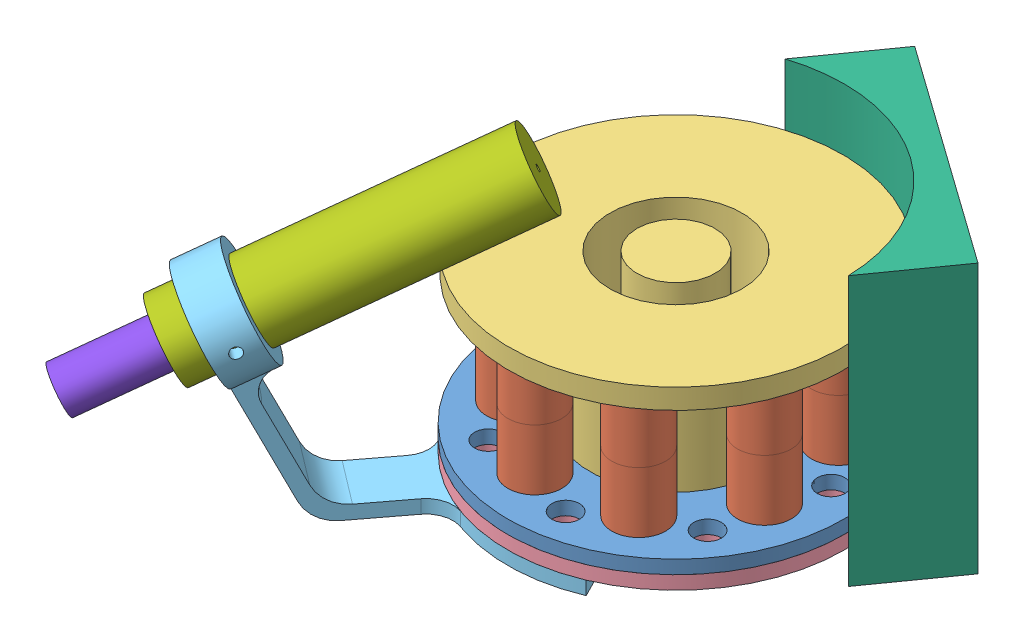
SolidWorks assembly Aseembly-FENG-BN7Q8T2, configuration Default. Lengths in mm.
Overall size (83.54 59.24 90.91).
26 component instances, 9 part files, 27 mates.
Components (placement in the parent):
- base_plate-3: base_plate [Default] at (-36.646 29.2594 17.7308) size (50 8 50)
- magnet_cyclo180-17: magnet_cyclo180 [Default] at (-36.646 30.2594 17.7308) x (-0.894675 0 0.446717) z (-0.446717 0 -0.894675) size (8 10 8)
- magnet_cyclo180-18: magnet_cyclo180 [Default] at (-27.3545 30.2594 32.5604) x (0.951763 0 -0.306835) z (0.306835 0 0.951763) size (8 10 8)
- magnet_cyclo180-19: magnet_cyclo180 [Default] at (-40.562 30.2594 34.787) x (0.889963 0 0.456033) z (-0.456033 0 0.889963) size (8 10 8)
- magnet_cyclo180-20: magnet_cyclo180 [Default] at (-51.4756 30.2594 27.0223) x (0.306835 0 0.951763) z (-0.951763 0 0.306835) size (8 10 8)
- magnet_cyclo180-21: magnet_cyclo180 [Default] at (-53.7022 30.2594 13.8147) x (-0.456033 0 0.889963) z (-0.889963 0 -0.456033) size (8 10 8)
- magnet_cyclo180-22: magnet_cyclo180 [Default] at (-45.9375 30.2594 2.9011) x (-0.951763 0 0.306835) z (-0.306835 0 -0.951763) size (8 10 8)
- magnet_cyclo180-23: magnet_cyclo180 [Default] at (-32.7299 30.2594 0.6746) x (-0.889963 0 -0.456033) z (0.456033 0 -0.889963) size (8 10 8)
- magnet_cyclo180-24: magnet_cyclo180 [Default] at (-21.8164 30.2594 8.4393) x (-0.306835 0 -0.951763) z (0.951763 0 -0.306835) size (8 10 8)
- magnet_cyclo180-25: magnet_cyclo180 [Default] at (-19.5898 30.2594 21.6468) x (0.456033 0 -0.889963) z (0.889963 0 0.456033) size (8 10 8)
- insulator-2: insulator [Default] at (-36.646 31.2594 17.7308) x (0.874558 0 0.48492) z (0 1 0) size (49.6 49.6 22)
- magnet_cyclo180-26: magnet_cyclo180 [Default] at (-51.4756 40.2594 27.0223) x (0.306835 0 0.951763) z (-0.951763 0 0.306835) size (8 10 8)
- magnet_cyclo180-27: magnet_cyclo180 [Default] at (-36.646 40.2594 17.7308) x (-0.894675 0 0.446717) z (-0.446717 0 -0.894675) size (8 10 8)
- magnet_cyclo180-28: magnet_cyclo180 [Default] at (-53.7022 40.2594 13.8147) x (-0.456033 0 0.889963) z (-0.889963 0 -0.456033) size (8 10 8)
- magnet_cyclo180-29: magnet_cyclo180 [Default] at (-45.9375 40.2594 2.9011) x (-0.951763 0 0.306835) z (-0.306835 0 -0.951763) size (8 10 8)
- magnet_cyclo180-30: magnet_cyclo180 [Default] at (-32.7299 40.2594 0.6746) x (-0.889963 0 -0.456033) z (0.456033 0 -0.889963) size (8 10 8)
- magnet_cyclo180-31: magnet_cyclo180 [Default] at (-21.8164 40.2594 8.4393) x (-0.306835 0 -0.951763) z (0.951763 0 -0.306835) size (8 10 8)
- magnet_cyclo180-32: magnet_cyclo180 [Default] at (-19.5898 40.2594 21.6468) x (0.456033 0 -0.889963) z (0.889963 0 0.456033) size (8 10 8)
- magnet_cyclo180-33: magnet_cyclo180 [Default] at (-27.3545 40.2594 32.5604) x (0.951763 0 -0.306835) z (0.306835 0 0.951763) size (8 10 8)
- magnet_cyclo180-34: magnet_cyclo180 [Default] at (-40.562 40.2594 34.787) x (0.889963 0 0.456033) z (-0.456033 0 0.889963) size (8 10 8)
- base_plate_insulating-2: base_plate_insulating [Default] at (-36.646 29.2594 17.7308) x (0.225197 0 -0.974313) z (-0.974313 0 -0.225197) size (50 2 50)
- mounting_bracket-2: mounting_bracket [Default] at (-62.4124 49.9171 59.3042) x (0.255584 -0.906308 -0.336576) z (0.548101 0.422618 -0.721789) size (47.08 43.47 29.39)
- stand-1: stand [Default] at (-36.646 22.2594 17.7308) x (0.814816 0 0.579719) z (-0.579719 0 0.814816) size (40 40 13.81)
- Retainer body 1.4-1: Retainer body 1.4 [Heaterless] at (12.071 297.1685 -153.6958) x (-0.548101 -0.422618 0.721789) z (-0.602179 -0.399525 -0.691202) size (43.5 11 11)
- Cathode tube 1.3-1: Cathode tube 1.3 [Default] at (-52.4436 60.06 39.5622) x (0.548101 0.422618 -0.721789) z (0.721789 0.197042 0.663472) size (53.5 6.5 6.5)
- alumina_insulator-2: alumina_insulator [Default] at (-63.4056 51.6076 53.998) x (0.565751 0.448273 0.692082) z (-0.548101 -0.422618 0.721789) size (9 9 10)
Mates (geometry in assembly coordinates):
- Concentric11: concentric aligned: circle of base_plate-3; circle of magnet_cyclo180-17
- Coincident19: coincident anti-aligned: plane of base_plate-3 through (-36.646 30.2594 17.7308) normal (0 1 0); plane of magnet_cyclo180-17 through (-36.646 30.2594 17.7308) normal (0 -1 0)
- Concentric12: concentric aligned: circle of base_plate-3; circle of magnet_cyclo180-18
- Coincident22: coincident anti-aligned: plane of base_plate-3 through (-27.3545 30.2594 32.5604) normal (0 1 0); plane of magnet_cyclo180-18 through (-27.3545 30.2594 32.5604) normal (0 -1 0)
- Coincident23: coincident anti-aligned: plane of base_plate-3 through (-36.646 31.2594 17.7308) normal (0 1 0); plane of insulator-2 through (-34.7063 31.2594 14.2325) normal (0 -1 0)
- Concentric13: concentric aligned: cylinder of base_plate-3 through (-38.7124 29.2594 10.521) axis (0 1 0) radius 1.05; circle of insulator-2
- Coincident28: coincident aligned: plane of base_plate-3 through (-36.646 29.2594 17.7308) normal (0 -1 0); plane of base_plate_insulating-1 through (-36.646 29.2594 17.7308) normal (0 -1 0)
- Coincident30: coincident anti-aligned: plane of base_plate-3 through (-36.646 29.2594 17.7308) normal (0 -1 0); plane of base_plate_insulating-2 through (-36.646 29.2594 17.7308) normal (0 1 0)
- Concentric19: concentric anti-aligned: circle of insulator-2; cylinder of base_plate_insulating-2 through (-40.2829 29.2594 24.29) axis (0 -1 0) radius 1.05
- Coincident32: coincident anti-aligned: plane of base_plate_insulating-2 through (-36.646 27.2594 17.7308) normal (0 -1 0); plane of mounting_bracket-2 through (-62.394 27.2594 46.0517) normal (0 1 0)
- Coincident33: coincident anti-aligned: plane of base_plate_insulating-2 through (-36.646 27.2594 17.7308) normal (0 -1 0); plane of mounting_bracket-2 through (-62.394 27.2594 46.0517) normal (0 1 0)
- Concentric25: concentric anti-aligned: cylinder of base_plate_insulating-2 through (-36.646 27.2594 17.7308) axis (0 1 0) radius 25; cylinder of stand-1 through (-36.646 62.2594 17.7308) axis (0 -1 0) radius 25
- Coincident36: coincident anti-aligned: plane of base_plate_insulating-2 through (-36.646 27.2594 17.7308) normal (0 -1 0); plane of stand-1 through (-36.646 27.2594 17.7308) normal (0 1 0)
- Coincident37: coincident anti-aligned: circle of base_plate_insulating-2; circle of stand-1
- Concentric26: concentric anti-aligned: circle of base_plate_insulating-2; circle of mounting_bracket-2
- Concentric27: concentric anti-aligned: circle of base_plate_insulating-2; cylinder of mounting_bracket-2 through (-33.3212 37.2594 37.4525) axis (0 -1 0) radius 2.05
- Concentric30: concentric aligned: circle of base_plate-3; circle of base_plate_insulating-2
- Concentric33: concentric aligned: circle of mounting_bracket-2; circle of Retainer body 1.4-1
- Distance1: distance = 4 mm aligned: plane of mounting_bracket-2 through (-69.8798 49.0719 55.9097) normal (-0.548101 -0.422618 0.721789); plane of Retainer body 1.4-1 through (-155.1317 168.2453 66.492) normal (-0.548101 -0.422618 0.721789)
- Concentric34: concentric: circle of Retainer body 1.4-1; circle of Cathode tube 1.3-1
- Distance2: distance = 1 mm: plane of Cathode tube 1.3-1 through (-46.6258 65.1511 31.7211) normal (0.548101 0.422618 -0.721789); plane of Retainer body 1.4-1 through (-132.1115 185.9953 36.1769) normal (-0.548101 -0.422618 0.721789)
- InPlace1: in place: plane of Retainer body 1.4-1 through (-155.1317 168.2453 66.492) normal (-0.548101 -0.422618 0.721789); plane of ? through (-33.937 -26.1675 44.6914) normal (-0.548101 -0.422618 0.721789); moOrthogonalPlaneRef_w of Retainer body 1.4-1 through (-155.1317 168.2453 66.492) normal (-0.548101 -0.422618 0.721789); plane of ? through (-33.937 -26.1675 44.6914) normal (0 0.862958 0.505275); plane of Retainer body 1.4-1 through (-155.1317 168.2453 66.492) normal (-0.548101 -0.422618 0.721789); plane of ? through (-33.937 -26.1675 44.6914) normal (0.836412 -0.276942 0.472988); plane of Retainer body 1.4-1 through (-155.1317 168.2453 66.492) normal (-0.548101 -0.422618 0.721789); unknown of ?
- Coincident45: coincident aligned: plane of Retainer body 1.4-1; plane of ?
- Coincident46: coincident aligned: moOrthogonalPlaneRef_w of Retainer body 1.4-1 through (-155.1317 168.2453 66.492) normal (-0.580487 0.813495 0.035512); plane of Part1^Aseembly-1 through (-155.1317 168.2453 66.492) normal (-0.580487 0.813495 0.035512)
- Coincident47: coincident anti-aligned: moOrthogonalPlaneRef_w of Retainer body 1.4-1 through (-155.1317 168.2453 66.492) normal (-0.602179 -0.399525 -0.691202); plane of Part1^Aseembly-1 through (-155.1317 168.2453 66.492) normal (0.602179 0.399525 0.691202)
- Concentric35: concentric aligned: circle of Retainer body 1.4-1; cylinder of alumina_insulator-2 through (-68.8866 47.3814 61.2159) axis (0.548101 0.422618 -0.721789) radius 3
- Coincident48: coincident anti-aligned: plane of Retainer body 1.4-1 through (-149.6507 172.4715 59.2741) normal (-0.548101 -0.422618 0.721789); plane of alumina_insulator-2 through (-63.4056 51.6076 53.998) normal (0.548101 0.422618 -0.721789)
